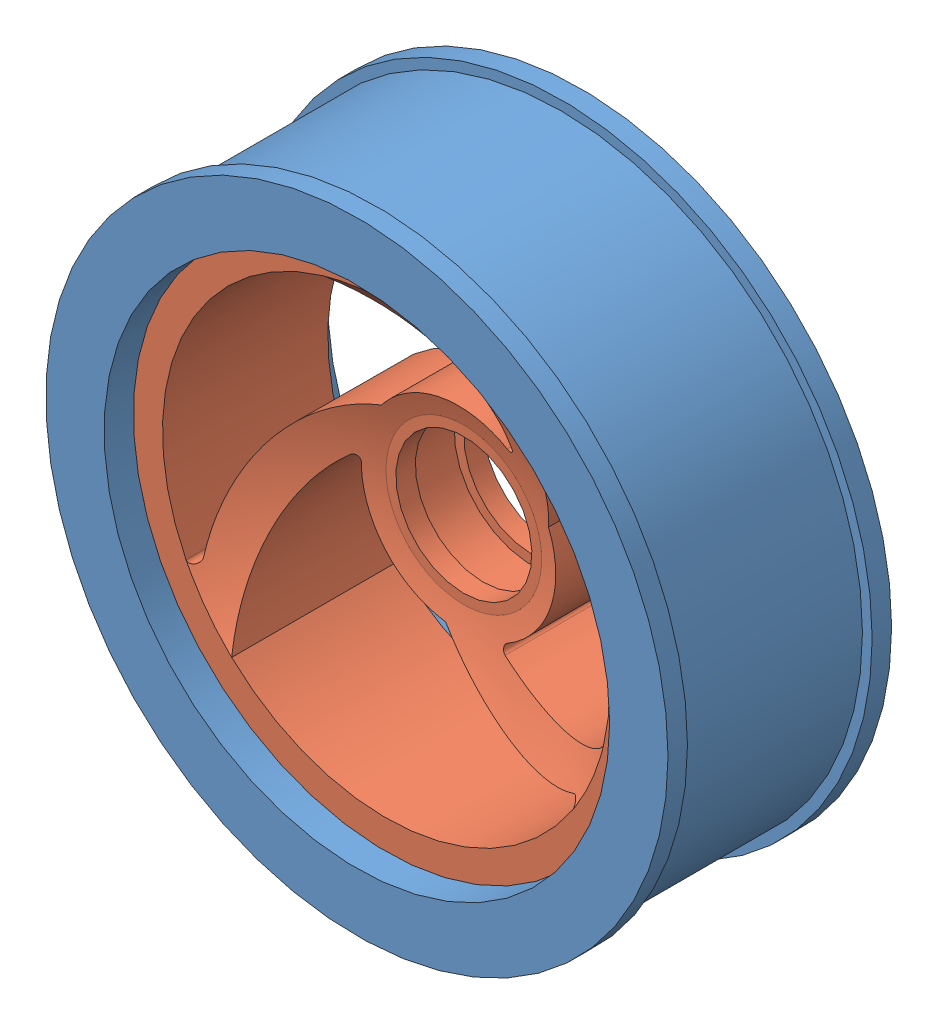
SolidWorks assembly jante, configuration Default. Lengths in mm.
Overall size (64.33 64.33 23).
2 component instances, 2 part files, 2 mates.
Components (placement in the parent):
- aro-1: aro [Default] at origin size (64 64 23)
- jante6-1: jante6 [Default] at (0 0 -8.5) x (0.986814 0.16186 0) z (0 0 1) size (56 56 17.95)
Mates (geometry in assembly coordinates):
- Concentric1: concentric anti-aligned: cylinder of aro-1; cylinder of jante6-1
- Coincident1: coincident anti-aligned: plane of aro-1 through (28 0 -8.5) normal (0 0 1); plane of jante6-1 through (0 0 -8.5) normal (0 0 -1)
